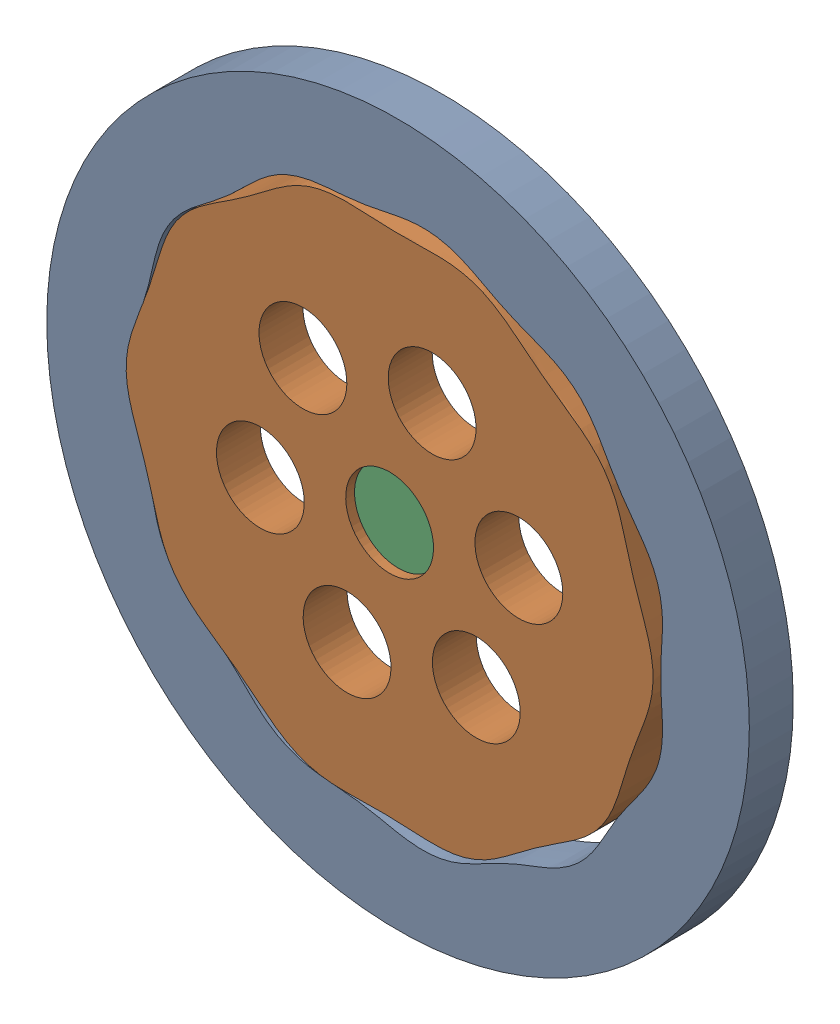
SolidWorks assembly TestPartAssem_2, configuration Default. Lengths in mm.
Overall size (80 80 5.02).
3 component instances, 3 part files, 5 mates.
Components (placement in the parent):
- cycloid_stator_2-1: cycloid_stator_2 [Default] at (-66.5524 49.5079 73.6773) size (80 80 5.02)
- cycloid_rotor_2-1: cycloid_rotor_2 [Default] at (-67.5124 49.2278 73.6773) x (-0.946416 0.322949 0) z (0 0 1) size (58.24 60 5)
- cycloidal_shaft_2-1: cycloidal_shaft_2 [Default] at (-66.5524 49.5079 73.6773) x (-0.959967 -0.280113 0) z (-0.280113 0.959967 0) size (11 4 10)
Mates (geometry in assembly coordinates):
- Coincident1: coincident aligned: plane of cycloid_stator_2-1 through (-66.5524 49.5079 78.6773) normal (0 0 1); plane of cycloid_rotor_2-1 through (-40.0663 39.8623 78.6773) normal (0 0 1)
- Concentric1: concentric aligned: cylinder of cycloid_stator_2-1 through (-66.5524 49.5079 78.6773) axis (0 0 -1) radius 40; cylinder of cycloidal_shaft_2-1 through (-66.5524 49.5079 75.6773) axis (0 0 -1) radius 5
- Coincident2: coincident aligned: plane of cycloid_stator_2-1 through (-66.5524 49.5079 73.6773) normal (0 0 -1); plane of cycloidal_shaft_2-1 through (-66.5524 49.5079 73.6773) normal (0 0 -1)
- Concentric2: concentric anti-aligned: cylinder of cycloid_rotor_2-1 through (-67.5124 49.2278 73.6773) axis (0 0 1) radius 5; cylinder of cycloidal_shaft_2-1 through (-67.5124 49.2278 77.6773) axis (0 0 -1) radius 5
- GearMate7: gear = 1 : 10 mm: circle of cycloid_rotor_2-1; circle of cycloidal_shaft_2-1
